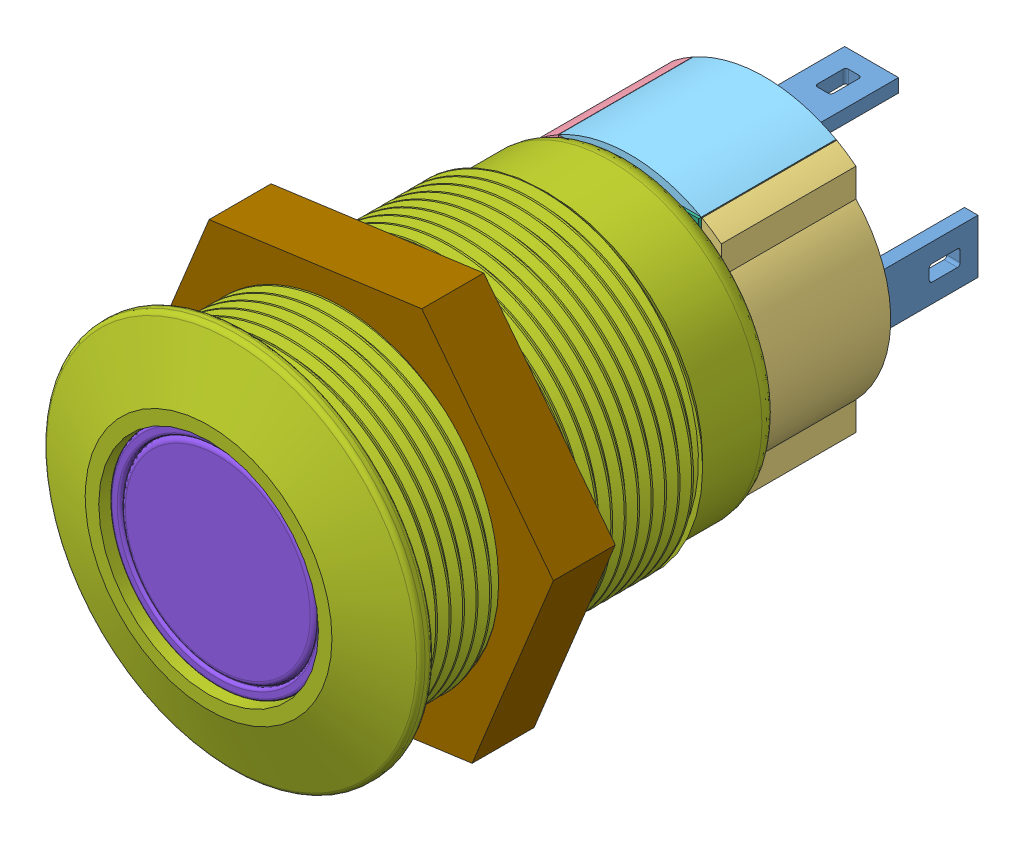
SolidWorks assembly 12mm flat Round head Waterproof Momentary Latching Metal Push Button Switch v11, configuration Default. Lengths in mm.
Overall size (15.79 14.76 24.73).
14 component instances, 9 part files, 0 mates.
Components (placement in the parent):
- 12mm flat Round head Waterproof Momentary Latching Metal Push Button Switch v11.step-1: 12mm flat Round head Waterproof Momentary Latching Metal Push Button Switch v11.step [Default] at origin size (15.79 14.76 24.73)
  - latching.step-1: latching.step [Default] at (0 0 -14.24) x (-1 0 0) z (0 0 -1) size (9.36 10.92 9.09)
    - solderlug.step-1: solderlug.step [Default] at origin size (2 0.5 4.09)
    - solderlug.step-2: solderlug.step [Default] x (0 1 0) z (0 0 1) size (2 0.5 4.09)
    - solderlug.step-3: solderlug.step [Default] x (-1 0 0) z (0 0 1) size (2 0.5 4.09)
    - solderlug.step-4: solderlug.step [Default] x (0 -1 0) z (0 0 1) size (2 0.5 4.09)
    - latching-0.step-1: latching-0.step [Default] at origin size (5.3 0.69 5)
    - latching-1.step-1: latching-1.step [Default] at origin size (2.03 9.53 5)
    - latching-2.step-1: latching-2.step [Default] at origin size (2.03 9.53 5)
    - latching-3.step-1: latching-3.step [Default] at origin size (5.3 0.69 5)
    - latching-4.step-1: latching-4.step [Default] at origin size (5.1 9.35 5.1)
  - Body.step-1: Body.step [Default] at origin size (14 14 15.64)
  - button.step-1: button.step [Default] at (0 0 -0.2414) size (8.06 8.06 1)
  - Nut.step-1: Nut.step [Default] at (0 0 -5.8) size (15.79 14.76 2.3)
